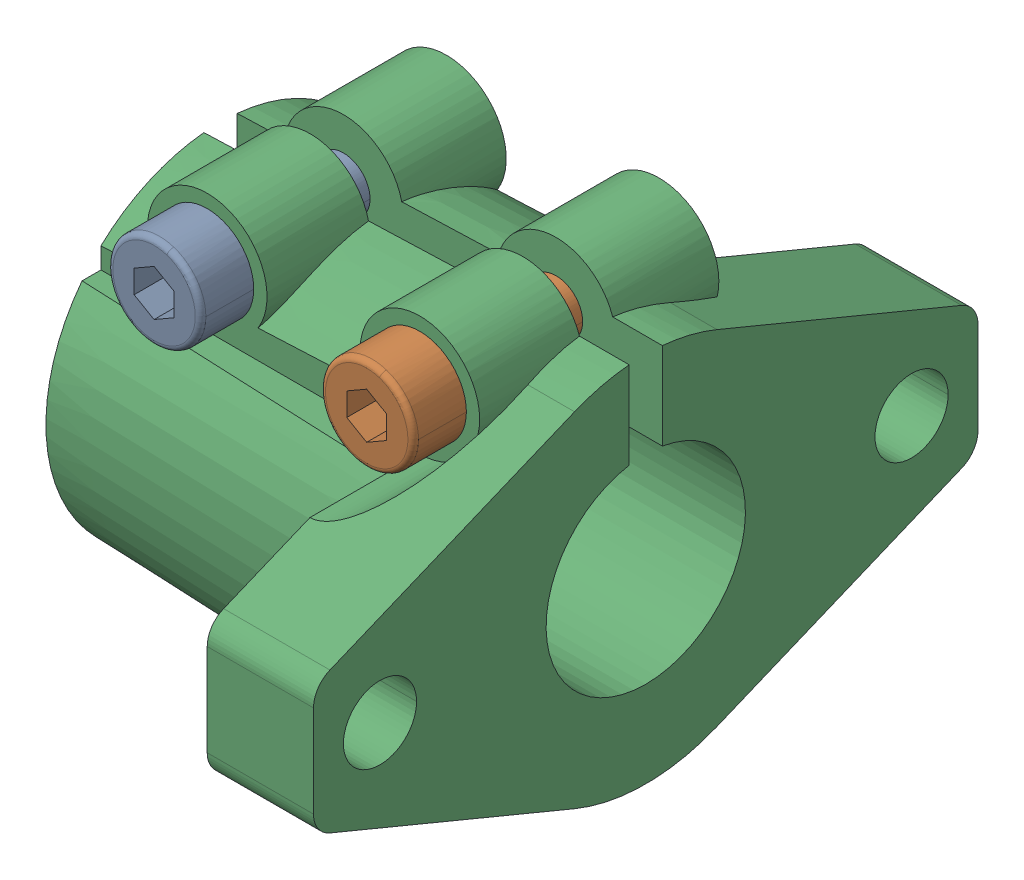
SolidWorks assembly SHFL15, configuration Default. Lengths in mm.
Overall size (32 31 50).
3 component instances, 2 part files, 0 mates.
Components (placement in the parent):
- SHFL15_3-1: SHFL15_3 [Default] at (-24 12.5 9) x (0 0 -1) z (-1 0 0) size (20 7 7)
- SHFL15_3-2: SHFL15_3 [Default] at (-8 12.5 9) x (0 0 -1) z (-1 0 0) size (20 7 7)
- SHFL15_6-1: SHFL15_6 [Default] at origin size (32 31 50)
